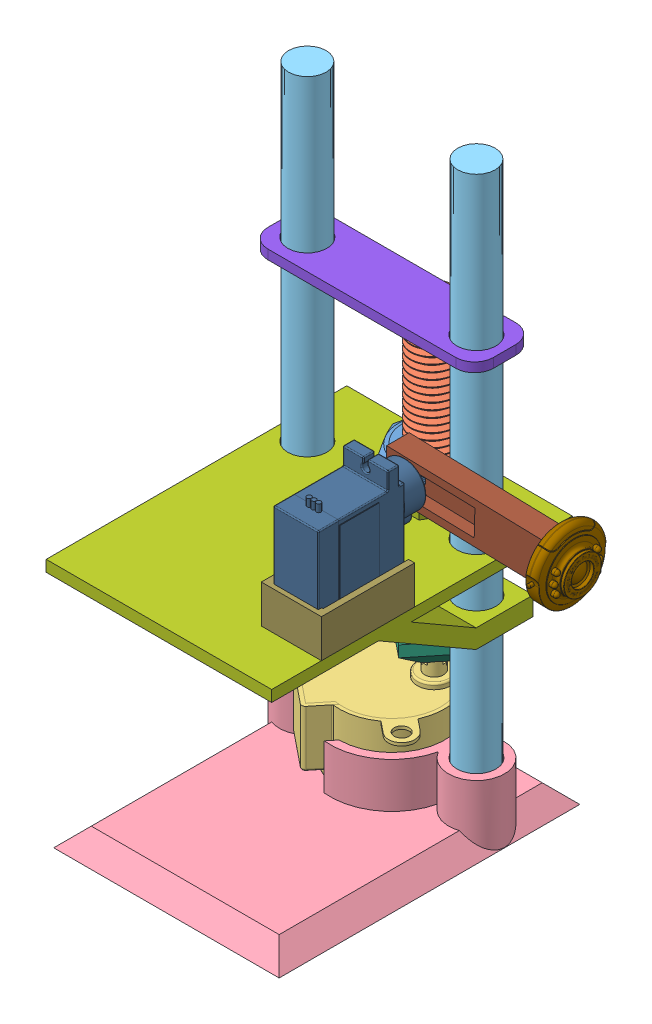
SolidWorks assembly upDownPlatform, configuration Default. Lengths in mm.
Overall size (96.1 155 86.09).
13 component instances, 12 part files, 32 mates.
Components (placement in the parent):
- 90592A028_STEEL HEX NUT-1: 90592A028_STEEL HEX NUT [90592A028] at (5.0301 67.4883 -26.2208) x (0.866025 0 0.5) z (-0.5 0 0.866025) size (19 11.37 21.94)
- ratthamnoonPrakitpong_1_threadedRod-1: ratthamnoonPrakitpong_1_threadedRod [1078N44] at (5.0301 69.5 -26.2208) x (0 -1 0) z (-0.358551 0 0.93351) size (76.86 12.46 12.62)
- 28BYJ48-1: 28BYJ48 [默认] at (0 19 -20) x (-0.777594 0 -0.628767) z (0 -1 0) size (42 32 29)
- base-1: base [Default] at origin size (60 17 80)
- rod-1: rod [Default] at (-22.5 0 -20) x (-0.241393 0 0.970427) z (-0.970427 0 -0.241393) size (10 150 10)
- rod-2: rod [Default] at (22.5 0 -20) size (10 150 10)
- leadScrewMount-1: leadScrewMount [Default] at (5.0301 29 -26.2208) x (0.777594 0 0.628767) z (-0.628767 0 0.777594) size (15 8 15)
- cameraMount-1: cameraMount [Default] at (0 59.4883 2) size (60 21 80)
- rodCap-1: rodCap [Default] at (0 107 -20) size (60 2.5 16)
- Webcam-1: Webcam [Défaut] at (61.5361 83.3406 -4.95) x (0 0 -1) z (0.999649 -0.026489 0) size (20 18.82 9.8)
- Servo-MG90S-1: Servo-MG90S [Default] at (22 79.1383 27.55) x (0 1 0) z (-1 0 0) size (32.2 32.5 12.4)
- servo extension-1: servo extension [Default] at (16.6476 90.032 -4.95) x (0.999649 -0.026489 0) z (-0.026489 -0.999649 0) size (43.55 6 11)
- stage servo mount-1: stage servo mount [Default] at (14 62.4883 28.75) x (0 0 -1) z (1 0 0) size (24.8 10.15 16)
Mates (geometry in assembly coordinates):
- Coincident2: coordinate: point of base-1
- Concentric1: concentric anti-aligned: circle of ratthamnoonPrakitpong_1_threadedRod-1; circle of 28BYJ48-1
- Concentric2: concentric aligned: circle of 90592A028_STEEL HEX NUT-1; circle of ratthamnoonPrakitpong_1_threadedRod-1
- Concentric3: concentric anti-aligned: cylinder of 28BYJ48-1 through (0 0 -20) axis (0 1 0) radius 14; cylinder of base-1 through (0 12 -20) axis (0 -1 0) radius 14.2
- Coincident5: coincident anti-aligned: plane of 28BYJ48-1 through (0 0 -20) normal (0 -1 0); plane of base-1 through (0 0 0) normal (0 1 0)
- Concentric4: concentric aligned: cylinder of base-1 through (-22.5 12 -20) axis (0 -1 0) radius 5.2; cylinder of rod-1 through (-22.5 150 -20) axis (0 -1 0) radius 5
- Coincident6: coincident anti-aligned: plane of base-1 through (0 0 0) normal (0 1 0); plane of rod-1 through (-22.5 0 -20) normal (0 -1 0)
- Coincident7: coincident anti-aligned: plane of base-1 through (0 0 0) normal (0 1 0); plane of rod-2 through (22.5 0 -20) normal (0 -1 0)
- Concentric5: concentric aligned: cylinder of base-1 through (22.5 12 -20) axis (0 -1 0) radius 5.2; cylinder of rod-2 through (22.5 150 -20) axis (0 -1 0) radius 5
- Perpendicular1: perpendicular: plane of 28BYJ48-1 through (-16.9942 4 -10.5933) normal (-0.628767 0 0.777594); plane of base-1 through (-16.7769 12 -13.5659) normal (0.777594 0 0.628767)
- Coincident9: coincident anti-aligned: plane of ratthamnoonPrakitpong_1_threadedRod-1 through (5.0301 32 -26.2208) normal (0 -1 0); plane of leadScrewMount-1 through (5.0301 32 -26.2208) normal (0 1 0)
- Symmetric1: symmetric aligned: plane of 28BYJ48-1 through (-0.7094 23 -28.9327) normal (-0.628767 0 0.777594); plane of 28BYJ48-1 through (1.1769 23 -31.2655) normal (0.628767 0 -0.777594); plane of leadScrewMount-1 through (5.0301 29 -26.2208) normal (-0.628767 0 0.777594)
- Concentric6: concentric anti-aligned: cylinder of 28BYJ48-1 through (5.0301 29 -26.2208) axis (0 -1 0) radius 2.5; cylinder of leadScrewMount-1 through (5.0301 24 -26.2208) axis (0 1 0) radius 2.7
- Coincident10: coincident anti-aligned: plane of 28BYJ48-1 through (5.0301 29 -26.2208) normal (0 1 0); plane of leadScrewMount-1 through (5.0301 29 -26.2208) normal (0 -1 0)
- Concentric7: concentric anti-aligned: cylinder of rod-2 through (22.5 150 -20) axis (0 -1 0) radius 5; cylinder of cameraMount-1 through (22.5 44.4883 -20) axis (0 1 0) radius 5.2
- Concentric8: concentric anti-aligned: cylinder of rod-1 through (-22.5 150 -20) axis (0 -1 0) radius 5; cylinder of cameraMount-1 through (-22.5 44.4883 -20) axis (0 1 0) radius 5.2
- Parallel3: parallel anti-aligned: plane of 90592A028_STEEL HEX NUT-1 through (15.9998 72.4883 -26.2208) normal (0.866025 0 -0.5); plane of cameraMount-1 through (22.2059 65.4883 -10.8206) normal (-0.866025 0 0.5)
- Coincident14: coincident anti-aligned: plane of 90592A028_STEEL HEX NUT-1 through (-0.4547 62.4883 -35.7208) normal (0 -1 0); plane of cameraMount-1 through (0 62.4883 2) normal (0 1 0)
- Coincident15: coincident anti-aligned: plane of ratthamnoonPrakitpong_1_threadedRod-1 through (5.0301 107 -26.2208) normal (0 1 0); plane of rodCap-1 through (25 107 -17) normal (0 -1 0)
- Concentric9: concentric aligned: cylinder of rod-1 through (-22.5 150 -20) axis (0 -1 0) radius 5; cylinder of rodCap-1 through (-22.5 109.5 -20) axis (0 -1 0) radius 5.2
- Concentric10: concentric aligned: cylinder of rod-2 through (22.5 150 -20) axis (0 -1 0) radius 5; cylinder of rodCap-1 through (22.5 109.5 -20) axis (0 -1 0) radius 5.2
- Coincident16: coincident anti-aligned: plane of cameraMount-1 through (0 62.4883 2) normal (0 1 0); plane of stage servo mount-1 through (14 62.4883 28.75) normal (0 -1 0)
- Distance1: distance = 13.25 mm aligned: plane of stage servo mount-1 through (14 67.6383 28.75) normal (0 0 1); plane of cameraMount-1 through (0 62.4883 42) normal (0 0 1)
- Coincident18: coincident aligned: plane of cameraMount-1 through (30 62.4883 2) normal (1 0 0); plane of stage servo mount-1 through (30 67.6383 28.75) normal (1 0 0)
- Coincident19: coincident anti-aligned: plane of Servo-MG90S-1 through (16 67.6383 9.05) normal (0 -1 0); plane of stage servo mount-1 through (14 67.6383 28.75) normal (0 1 0)
- Coincident20: coincident anti-aligned: plane of Servo-MG90S-1 through (22 79.1383 6.05) normal (0 0 -1); plane of stage servo mount-1 through (15.625 67.6383 6.05) normal (0 0 1)
- Symmetric2: symmetric aligned: plane of Servo-MG90S-1 through (22 79.1383 27.55) normal (-1 0 0); plane of stage servo mount-1 through (28.375 67.6383 9.05) normal (-1 0 0); plane of stage servo mount-1 through (15.625 67.6383 9.05) normal (1 0 0)
- Concentric11: concentric aligned: cylinder of Servo-MG90S-1 through (22 84.3883 -1.45) axis (0 0 1) radius 5.75; line of servo extension-1 through (22 84.3883 -4.95) axis (0 0 1)
- Coincident21: coincident anti-aligned: plane of Servo-MG90S-1 through (22 84.3883 -4.95) normal (0 0 -1); plane of servo extension-1 through (16.6476 90.032 -4.95) normal (0 0 1)
- Concentric12: concentric aligned: cylinder of Webcam-1 through (60.4432 83.3696 -4.95) axis (-0.999649 0.026489 0) radius 0.7; line of servo extension-1 through (62.2134 83.3227 -4.95) axis (-0.999649 0.026489 0)
- Distance3: distance = 4 mm anti-aligned: plane of Webcam-1 through (56.0381 83.4863 -4.95) normal (-0.999649 0.026489 0); plane of servo extension-1 through (60.1823 88.8784 -1.95) normal (0.999649 -0.026489 0)
- Parallel4: parallel aligned: plane of Webcam-1 through (61.5361 83.3406 -4.95) normal (0.026489 0.999649 0); plane of servo extension-1 through (16.6476 90.032 -1.95) normal (0.026489 0.999649 0)
